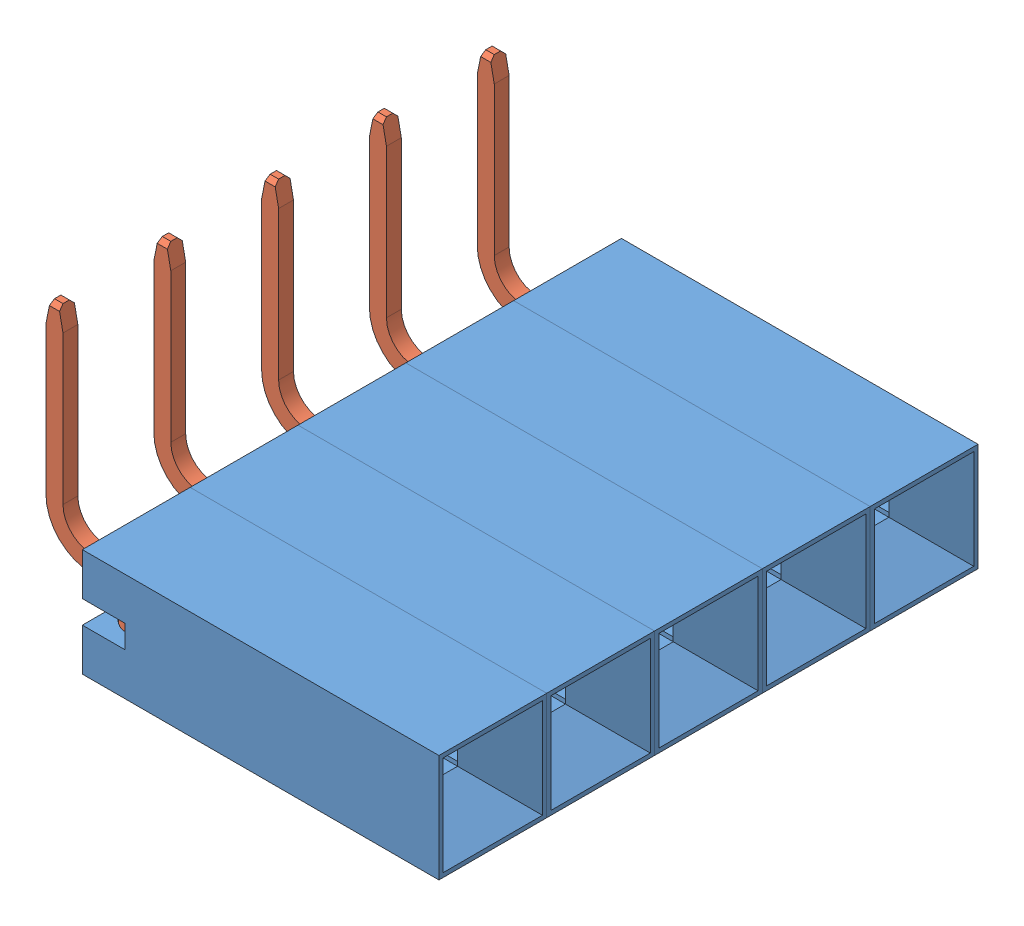
SolidWorks assembly H254_90deg_5pin, configuration Default. Lengths in mm.
Overall size (10.36 6.14 12.7).
15 component instances, 2 part files, 8 mates.
Components (placement in the parent):
- FrameAndPin_H254_90deg-1: FrameAndPin_H254_90deg [Default] at origin size (10.36 6.14 2.54)
  - frame_H254-1: frame_H254 [Default] at origin size (8.4 2.54 2.54)
  - pin-90deg-1: pin-90deg [Default] at (-0.0461 1.2682 1.27) x (0 0 -1) z (0.999998 -0.002105 0) size (1.95 5.07 7.58)
- FrameAndPin_H254_90deg-2: FrameAndPin_H254_90deg [Default] at (0 0 -2.54) size (10.36 6.14 2.54)
  - frame_H254-1: frame_H254 [Default] at origin size (8.4 2.54 2.54)
  - pin-90deg-1: pin-90deg [Default] at (-0.0461 1.2682 1.27) x (0 0 -1) z (0.999998 -0.002105 0) size (1.95 5.07 7.58)
- FrameAndPin_H254_90deg-4: FrameAndPin_H254_90deg [Default] at (0 0 -5.08) size (10.36 6.14 2.54)
  - frame_H254-1: frame_H254 [Default] at origin size (8.4 2.54 2.54)
  - pin-90deg-1: pin-90deg [Default] at (-0.0461 1.2682 1.27) x (0 0 -1) z (0.999998 -0.002105 0) size (1.95 5.07 7.58)
- FrameAndPin_H254_90deg-5: FrameAndPin_H254_90deg [Default] at (0 0 -7.62) size (10.36 6.14 2.54)
  - frame_H254-1: frame_H254 [Default] at origin size (8.4 2.54 2.54)
  - pin-90deg-1: pin-90deg [Default] at (-0.0461 1.2682 1.27) x (0 0 -1) z (0.999998 -0.002105 0) size (1.95 5.07 7.58)
- FrameAndPin_H254_90deg-6: FrameAndPin_H254_90deg [Default] at (0 0 -10.16) size (10.36 6.14 2.54)
  - frame_H254-1: frame_H254 [Default] at origin size (8.4 2.54 2.54)
  - pin-90deg-1: pin-90deg [Default] at (-0.0461 1.2682 1.27) x (0 0 -1) z (0.999998 -0.002105 0) size (1.95 5.07 7.58)
Mates (geometry in assembly coordinates):
- Coincident1: coincident aligned: line of FrameAndPin_H254_90deg-1/frame_H254-1 through (8.4 8.4 2.54) axis (0 -1 0); line of FrameAndPin_H254_90deg-2/frame_H254-1 through (8.4 8.4 2.54) axis (0 -1 0)
- Coincident2: coincident aligned: line of FrameAndPin_H254_90deg-1/frame_H254-1 through (2.54 8.4 0) axis (0 0 1); line of FrameAndPin_H254_90deg-2/frame_H254-1 through (2.54 8.4 0) axis (0 0 1)
- Coincident3: coincident aligned: line of FrameAndPin_H254_90deg-2/frame_H254-1 through (8.4 2.54 -2.54) axis (-1 0 0); line of FrameAndPin_H254_90deg-4/frame_H254-1 through (8.4 2.54 -2.54) axis (-1 0 0)
- Coincident4: coincident aligned: line of FrameAndPin_H254_90deg-2/frame_H254-1 through (8.4 0 -2.54) axis (0 1 0); line of FrameAndPin_H254_90deg-4/frame_H254-1 through (8.4 0 -2.54) axis (0 1 0)
- Coincident5: coincident anti-aligned: plane of FrameAndPin_H254_90deg-4/frame_H254-1 through (0 0 -5.08) normal (0 0 -1); plane of FrameAndPin_H254_90deg-5/frame_H254-1 through (0 0 -5.08) normal (0 0 1)
- Coincident7: coincident aligned: line of FrameAndPin_H254_90deg-4/frame_H254-1 through (8.4 2.54 -2.54) axis (0 0 -1); line of FrameAndPin_H254_90deg-5/frame_H254-1 through (8.4 2.54 -5.08) axis (0 0 -1)
- Coincident8: coincident anti-aligned: plane of FrameAndPin_H254_90deg-5/frame_H254-1 through (0 0 -7.62) normal (0 0 -1); plane of FrameAndPin_H254_90deg-6/frame_H254-1 through (0.2662 0.2464 -7.62) normal (0 0 1)
- Coincident9: coincident aligned: line of FrameAndPin_H254_90deg-5/frame_H254-1 through (8.4 2.54 -5.08) axis (0 0 -1); line of FrameAndPin_H254_90deg-6/frame_H254-1 through (8.6662 2.7864 -7.62) axis (0 0 -1)
